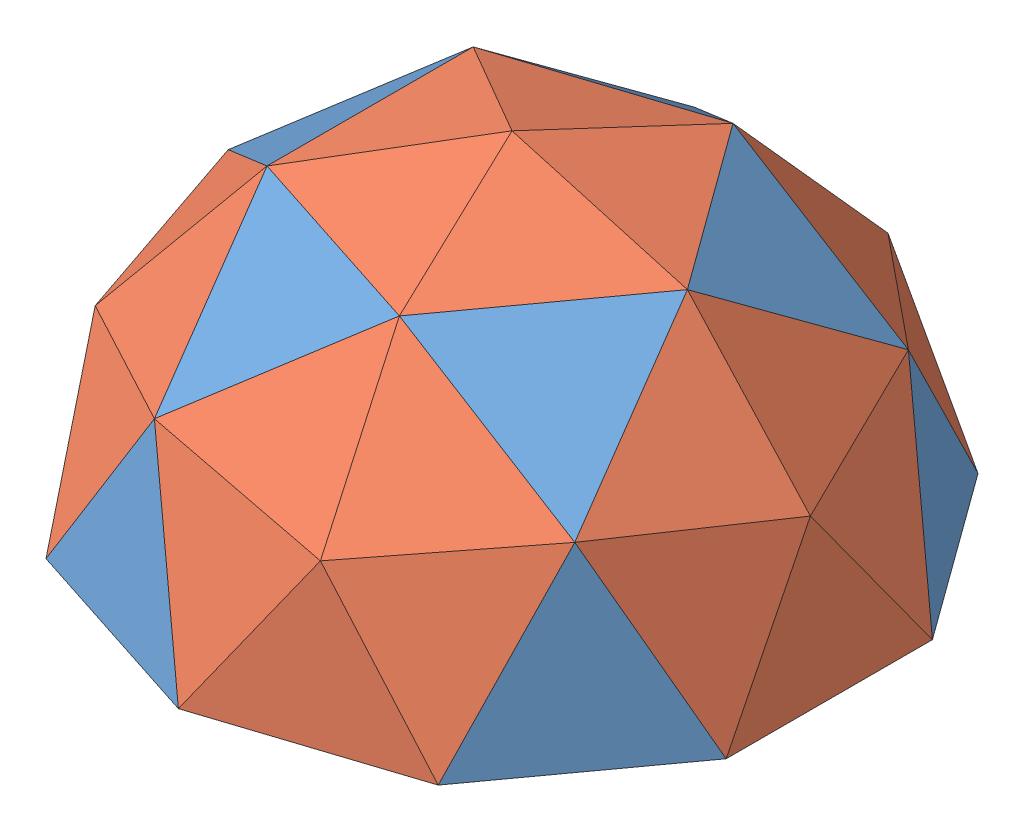
SolidWorks assembly Geocork1.0, configuration По умолчанию. Lengths in mm.
Overall size (6144.42 3896.71 6094.98).
40 component instances, 2 part files, 25 mates.
Components (placement in the parent):
- BBB^Geocork1.0-38: BBB^Geocork1.0 [По умолчанию] at (-850.6508 525.7311 2618.034) x (-0.952822 -0.059759 -0.29759) z (0.303531 -0.187592 -0.934172) size (1850.67 1659.13 60) (virtual)
- AAB^Geocork1.0-48: AAB^Geocork1.0 [По умолчанию] at (758.6906 2670.7024 551.221) x (-0.963409 0.262502 0.054179) z (-0.268035 -0.943522 -0.194739) size (1637.1 1559.6 60) (virtual)
- AAB^Geocork1.0-49: AAB^Geocork1.0 [По умолчанию] at (-289.794 2670.7024 891.8943) x (-0.349237 0.262502 -0.899514) z (0.10238 -0.943522 -0.315094) size (1637.1 1559.6 60) (virtual)
- AAB^Geocork1.0-50: AAB^Geocork1.0 [По умолчанию] at (-937.7931 2670.7024 0) x (0.747569 0.262502 -0.61011) z (0.331309 -0.943522 0) size (1637.1 1559.6 60) (virtual)
- AAB^Geocork1.0-51: AAB^Geocork1.0 [По умолчанию] at (-289.794 2670.7024 -891.8943) x (0.81126 0.262502 0.522446) z (0.10238 -0.943522 0.315094) size (1637.1 1559.6 60) (virtual)
- AAB^Geocork1.0-52: AAB^Geocork1.0 [По умолчанию] at (758.6906 2670.7024 -551.221) x (-0.246182 0.262502 0.932999) z (-0.268035 -0.943522 0.194739) size (1637.1 1559.6 60) (virtual)
- BBB^Geocork1.0-39: BBB^Geocork1.0 [По умолчанию] at (-2752.7638 525.7311 0) x (-0.011413 -0.059759 -0.998148) z (0.982247 -0.187592 0) size (1850.67 1659.13 60) (virtual)
- BBB^Geocork1.0-40: BBB^Geocork1.0 [По умолчанию] at (-850.6508 525.7311 -2618.034) x (0.945768 -0.059759 -0.319299) z (0.303531 -0.187592 0.934172) size (1850.67 1659.13 60) (virtual)
- BBB^Geocork1.0-41: BBB^Geocork1.0 [По умолчанию] at (2227.0327 525.7311 -1618.034) x (0.59593 -0.059759 0.80081) z (-0.794654 -0.187592 0.57735) size (1850.67 1659.13 60) (virtual)
- BBB^Geocork1.0-42: BBB^Geocork1.0 [По умолчанию] at (2227.0327 525.7311 1618.034) x (-0.577463 -0.059759 0.814227) z (-0.794654 -0.187592 -0.57735) size (1850.67 1659.13 60) (virtual)
- BBB^Geocork1.0-43: BBB^Geocork1.0 [По умолчанию] at (-525.7311 2227.0327 1618.034) x (0.964235 0.036933 0.262464) z (0.187592 -0.794654 -0.57735) size (1850.67 1659.13 60) (virtual)
- AAB^Geocork1.0-53: AAB^Geocork1.0 [По умолчанию] at (-70.0293 935.1748 2670.7024) x (0.457316 0.843008 -0.283197) z (0.02474 -0.330384 -0.943522) size (1637.1 1559.6 60) (virtual)
- AAB^Geocork1.0-58: AAB^Geocork1.0 [По умолчанию] at (1626.4544 935.1748 2119.4814) x (-0.734672 -0.194973 0.649802) z (-0.574604 -0.330384 -0.748783) size (1637.1 1559.6 60) (virtual)
- AAB^Geocork1.0-63: AAB^Geocork1.0 [По умолчанию] at (867.7638 355.5867 2670.7024) x (-0.611006 0.78604 0.093872) z (-0.306569 -0.125624 -0.943522) size (1637.1 1559.6 60) (virtual)
- AAB^Geocork1.0-68: AAB^Geocork1.0 [По умолчанию] at (109.0732 1872.9679 2119.4814) x (0.99391 -0.102798 0.039693) z (-0.038534 -0.661694 -0.748783) size (1637.1 1559.6 60) (virtual)
- AAB^Geocork1.0-73: AAB^Geocork1.0 [По умолчанию] at (1157.5578 1872.9679 1778.8081) x (0.257221 -0.744305 0.616318) z (-0.408949 -0.661694 -0.628428) size (1637.1 1559.6 60) (virtual)
- AAB^Geocork1.0-54: AAB^Geocork1.0 [По умолчанию] at (-2561.6291 935.1748 758.6906) x (0.410654 0.843008 0.347421) z (0.904988 -0.330384 -0.268035) size (1637.1 1559.6 60) (virtual)
- AAB^Geocork1.0-55: AAB^Geocork1.0 [По умолчанию] at (-1513.1446 935.1748 -2201.8058) x (-0.203517 0.843008 0.497914) z (0.534573 -0.330384 0.777868) size (1637.1 1559.6 60) (virtual)
- AAB^Geocork1.0-56: AAB^Geocork1.0 [По умолчанию] at (1626.4544 935.1748 -2119.4814) x (-0.536435 0.843008 -0.039693) z (-0.574604 -0.330384 0.748783) size (1637.1 1559.6 60) (virtual)
- AAB^Geocork1.0-57: AAB^Geocork1.0 [По умолчанию] at (2518.3486 935.1748 891.8943) x (-0.128018 0.843008 -0.522446) z (-0.889698 -0.330384 -0.315094) size (1637.1 1559.6 60) (virtual)
- AAB^Geocork1.0-64: AAB^Geocork1.0 [По умолчанию] at (-2271.8351 355.5867 1650.5848) x (-0.278089 0.78604 -0.552094) z (0.802608 -0.125624 -0.583129) size (1637.1 1559.6 60) (virtual)
- AAB^Geocork1.0-65: AAB^Geocork1.0 [По умолчанию] at (-2271.8351 355.5867 -1650.5848) x (0.439138 0.78604 -0.435084) z (0.802608 -0.125624 0.583129) size (1637.1 1559.6 60) (virtual)
- AAB^Geocork1.0-66: AAB^Geocork1.0 [По умолчанию] at (867.7638 355.5867 -2670.7024) x (0.549491 0.78604 0.283197) z (-0.306569 -0.125624 0.943522) size (1637.1 1559.6 60) (virtual)
- AAB^Geocork1.0-67: AAB^Geocork1.0 [По умолчанию] at (2808.1427 355.5867 0) x (-0.099534 0.78604 0.61011) z (-0.992078 -0.125624 0) size (1637.1 1559.6 60) (virtual)
- AAB^Geocork1.0-59: AAB^Geocork1.0 [По умолчанию] at (-1513.1446 935.1748 2201.8058) x (-0.845025 -0.194973 -0.497914) z (0.534573 -0.330384 -0.777868) size (1637.1 1559.6 60) (virtual)
- AAB^Geocork1.0-60: AAB^Geocork1.0 [По умолчанию] at (-2561.6291 935.1748 -758.6906) x (0.212418 -0.194973 -0.95753) z (0.904988 -0.330384 0.268035) size (1637.1 1559.6 60) (virtual)
- AAB^Geocork1.0-61: AAB^Geocork1.0 [По умолчанию] at (-70.0293 935.1748 -2670.7024) x (0.976306 -0.194973 -0.093872) z (0.02474 -0.330384 0.943522) size (1637.1 1559.6 60) (virtual)
- AAB^Geocork1.0-62: AAB^Geocork1.0 [По умолчанию] at (2518.3486 935.1748 -891.8943) x (0.390973 -0.194973 0.899514) z (-0.889698 -0.330384 0.315094) size (1637.1 1559.6 60) (virtual)
- AAB^Geocork1.0-74: AAB^Geocork1.0 [По умолчанию] at (-1334.042 1872.9679 1650.5848) x (-0.506667 -0.744305 0.435084) z (0.471299 -0.661694 -0.583129) size (1637.1 1559.6 60) (virtual)
- AAB^Geocork1.0-75: AAB^Geocork1.0 [По умолчанию] at (-1982.0411 1872.9679 -758.6906) x (-0.570359 -0.744305 -0.347421) z (0.700228 -0.661694 0.268035) size (1637.1 1559.6 60) (virtual)
- AAB^Geocork1.0-76: AAB^Geocork1.0 [По умолчанию] at (109.0732 1872.9679 -2119.4814) x (0.154166 -0.744305 -0.649802) z (-0.038534 -0.661694 0.748783) size (1637.1 1559.6 60) (virtual)
- AAB^Geocork1.0-77: AAB^Geocork1.0 [По умолчанию] at (2049.4521 1872.9679 -551.221) x (0.665639 -0.744305 -0.054179) z (-0.724043 -0.661694 0.194739) size (1637.1 1559.6 60) (virtual)
- AAB^Geocork1.0-69: AAB^Geocork1.0 [По умолчанию] at (-1982.0411 1872.9679 758.6906) x (0.269385 -0.102798 0.95753) z (0.700228 -0.661694 -0.268035) size (1637.1 1559.6 60) (virtual)
- AAB^Geocork1.0-70: AAB^Geocork1.0 [По умолчанию] at (-1334.042 1872.9679 -1650.5848) x (-0.827421 -0.102798 0.552094) z (0.471299 -0.661694 0.583129) size (1637.1 1559.6 60) (virtual)
- AAB^Geocork1.0-71: AAB^Geocork1.0 [По умолчанию] at (1157.5578 1872.9679 -1778.8081) x (-0.780759 -0.102798 -0.616318) z (-0.408949 -0.661694 0.628428) size (1637.1 1559.6 60) (virtual)
- AAB^Geocork1.0-72: AAB^Geocork1.0 [По умолчанию] at (2049.4521 1872.9679 551.221) x (0.344885 -0.102798 -0.932999) z (-0.724043 -0.661694 -0.194739) size (1637.1 1559.6 60) (virtual)
- BBB^Geocork1.0-44: BBB^Geocork1.0 [По умолчанию] at (-1701.3016 2227.0327 0) x (0.048346 0.036933 0.998148) z (0.607062 -0.794654 0) size (1850.67 1659.13 60) (virtual)
- BBB^Geocork1.0-45: BBB^Geocork1.0 [По умолчанию] at (-525.7311 2227.0327 -1618.034) x (-0.934355 0.036933 0.354425) z (0.187592 -0.794654 0.57735) size (1850.67 1659.13 60) (virtual)
- BBB^Geocork1.0-46: BBB^Geocork1.0 [По умолчанию] at (1376.3819 2227.0327 -1000) x (-0.62581 0.036933 -0.779101) z (-0.491123 -0.794654 0.356822) size (1850.67 1659.13 60) (virtual)
- BBB^Geocork1.0-47: BBB^Geocork1.0 [По умолчанию] at (1376.3819 2227.0327 1000) x (0.547583 0.036933 -0.835936) z (-0.491123 -0.794654 -0.356822) size (1850.67 1659.13 60) (virtual)
Mates (geometry in assembly coordinates):
- На месте1: in place: plane of ? through (-70.8876 43.8109 218.1695) normal (0.303531 -0.187592 -0.934172); moOrthogonalPlaneRef_w of ?; unknown of ?; unknown of BBB^Geocork1.0-38
- Совпадение1: coincident aligned: plane of BBB^Geocork1.0-38; plane of assembly
- Совпадение2: coincident aligned: plane of BBB^Geocork1.0-38 through (-850.6508 525.7311 2618.034) normal (0 0.980427 -0.196881); moOrthogonalPlaneRef_w of assembly
- Совпадение3: coincident anti-aligned: plane of BBB^Geocork1.0-38 through (-850.6508 525.7311 2618.034) normal (-0.952822 -0.059759 -0.29759); moOrthogonalPlaneRef_w of assembly
- На месте2: in place: plane of ? through (63.2242 222.5585 45.9351) normal (-0.268035 -0.943522 -0.194739); unknown of ?; unknown of ?; unknown of AAB^Geocork1.0-48
- Совпадение4: coincident aligned: plane of AAB^Geocork1.0-48; plane of assembly
- Совпадение5: coincident aligned: plane of AAB^Geocork1.0-48 through (758.6906 2670.7024 551.221) normal (0 0.202135 -0.979358); moOrthogonalPlaneRef_w of assembly
- Совпадение6: coincident anti-aligned: plane of AAB^Geocork1.0-48 through (758.6906 2670.7024 551.221) normal (-0.963409 0.262502 0.054179); moOrthogonalPlaneRef_w of assembly
- Совпадение8: coincident: point of AAB^Geocork1.0-49; point of BBB^Geocork1.0-43
- Совпадение11: coincident: point of AAB^Geocork1.0-49; point of BBB^Geocork1.0-43
- Совпадение12: coincident: point of BBB^Geocork1.0-38; point of BBB^Geocork1.0-43
- Совпадение13: coincident: point of BBB^Geocork1.0-38; point of AAB^Geocork1.0-53
- Совпадение15: coincident: point of AAB^Geocork1.0-53; point of assembly
- Совпадение16: coincident: point of AAB^Geocork1.0-58; point of assembly
- Совпадение17: coincident: point of BBB^Geocork1.0-42; point of AAB^Geocork1.0-58
- Совпадение18: coincident: point of AAB^Geocork1.0-53; point of AAB^Geocork1.0-58
- Совпадение23: coincident: point of AAB^Geocork1.0-63; point of assembly
- Совпадение24: coincident: point of AAB^Geocork1.0-63; point of assembly
- Совпадение25: coincident: point of AAB^Geocork1.0-58; point of AAB^Geocork1.0-63
- Совпадение26: coincident: point of AAB^Geocork1.0-48; point of AAB^Geocork1.0-68
- Совпадение27: coincident: point of BBB^Geocork1.0-38; point of AAB^Geocork1.0-68
- Совпадение28: coincident: point of AAB^Geocork1.0-58; point of AAB^Geocork1.0-68
- Совпадение29: coincident: point of AAB^Geocork1.0-68; point of AAB^Geocork1.0-73
- Совпадение30: coincident: point of AAB^Geocork1.0-58; point of AAB^Geocork1.0-73
- Совпадение31: coincident: point of AAB^Geocork1.0-68; point of AAB^Geocork1.0-73
